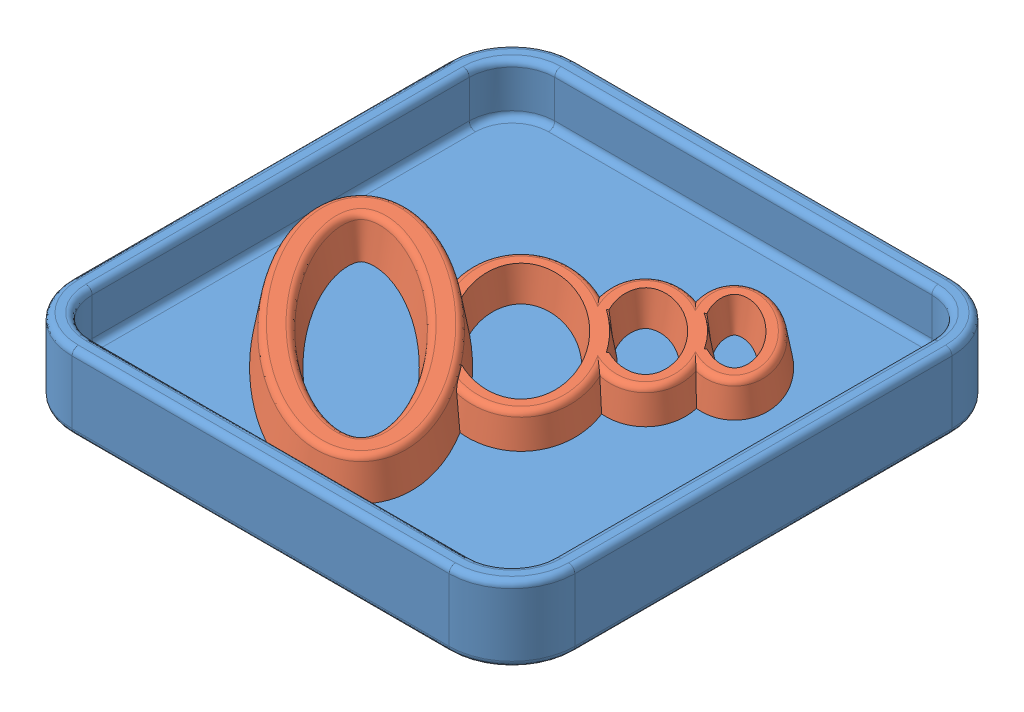
SolidWorks assembly Assem4, configuration Default. Lengths in mm.
Overall size (40 6 40).
2 component instances, 2 part files, 2 mates.
Components (placement in the parent):
- Tile-1: Tile [Default] at (13.9654 17.1489 31.7057) size (40 6 40)
- WormHole-1: WormHole [Default] at (13.9361 19.1489 31.3057) size (36.01 3.6 36.03)
Mates (geometry in assembly coordinates):
- Coincident1: coincident anti-aligned: plane of Tile-1 through (-1.0346 19.1489 46.7057) normal (0 1 0); plane of WormHole-1 through (17.0987 19.1489 46.9443) normal (0 -1 0)
- Coincident2: coincident anti-aligned: line of Tile-1 through (28.9654 19.1489 13.8057) axis (-1 0 0); line of WormHole-1 through (-3.5639 19.1489 13.8057) axis (1 0 0)
